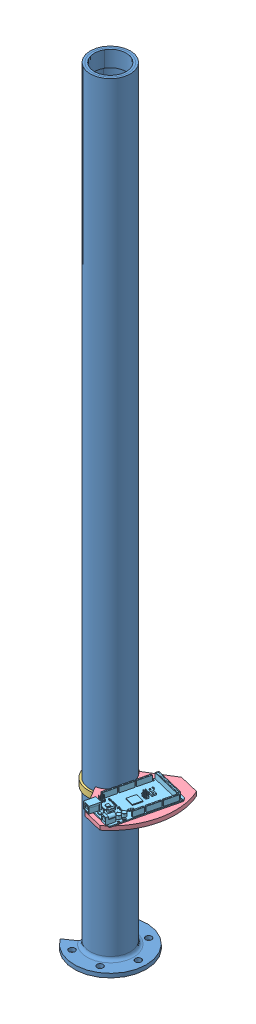
SolidWorks assembly Assem2, configuration Default. Lengths in mm.
Overall size (171.96 1216.15 144.23).
5 component instances, 5 part files, 10 mates.
Components (placement in the parent):
- LinearAct-1: LinearAct [Default] at (531.164 176.228 788.3631) size (103.96 1216.15 114.3)
- elec_right-1: elec_right [Default] at (531.164 411.1336 788.3631) x (-0.233481 0 0.972361) z (0.972361 0 0.233481) size (41.49 10.16 97.03)
- elec_left-1: elec_left [Default] at (531.164 400.9736 788.3631) x (0.233481 0 -0.972361) z (0.972361 0 0.233481) size (41.49 10.16 97.03)
- elec_platform-1: elec_platform [Default] at (631.4377 411.1336 812.4406) x (0.233481 0 -0.972361) z (0.972361 0 0.233481) size (127 6.35 88.85)
- ArduinoMega-1: ArduinoMega [Default] at (591.4633 419.1346 809.3726) x (-0.233481 0 0.972361) z (0 -1 0) size (107.95 53.42 12.95)
Mates (geometry in assembly coordinates):
- Concentric1: concentric aligned: cylinder of LinearAct-1 through (531.164 1392.38 788.3631) axis (0 -1 0) radius 31.75; cylinder of elec_left-1 through (531.164 411.1336 788.3631) axis (0 -1 0) radius 32.004
- Concentric2: concentric anti-aligned: cylinder of LinearAct-1 through (531.164 1392.38 788.3631) axis (0 -1 0) radius 31.75; cylinder of elec_right-1 through (531.164 400.9736 788.3631) axis (0 1 0) radius 32.004
- Coincident1: coincident anti-aligned: plane of elec_right-1 through (562.2834 400.9736 795.8355) normal (-0.233481 0 0.972361); plane of elec_left-1 through (562.2834 411.1336 795.8355) normal (0.233481 0 -0.972361)
- Coincident2: coincident aligned: plane of elec_right-1 through (531.164 411.1336 788.3631) normal (0 1 0); plane of elec_left-1 through (531.164 411.1336 788.3631) normal (0 1 0)
- Concentric10: concentric aligned: cylinder of LinearAct-1 through (531.164 1392.38 788.3631) axis (0 -1 0) radius 31.75; cylinder of elec_platform-1 through (531.164 417.4836 788.3631) axis (0 -1 0) radius 32.004
- Coincident6: coincident aligned: plane of elec_left-1 through (539.222 406.0536 820.9599) normal (-0.852659 0 0.522467); plane of elec_platform-1 through (538.357 417.4836 819.5483) normal (-0.852659 0 0.522467)
- Coincident7: coincident anti-aligned: plane of elec_left-1 through (531.164 411.1336 788.3631) normal (0 1 0); plane of elec_platform-1 through (531.164 411.1336 788.3631) normal (0 -1 0)
- Coincident8: coincident anti-aligned: plane of elec_platform-1 through (531.164 417.4836 788.3631) normal (0 1 0); plane of ArduinoMega-1 through (605.5724 417.4836 865.0044) normal (0 -1 0)
- Distance1: distance = 6.35 mm aligned: plane of ArduinoMega-1 through (553.6326 417.4836 852.5327) normal (-0.233481 0 0.972361); plane of elec_platform-1 through (564.1116 417.4836 861.5794) normal (-0.233481 0 0.972361)
- Distance2: distance = 5.08 mm anti-aligned: plane of ArduinoMega-1 through (577.3543 417.4836 753.7408) normal (-0.972361 0 -0.233481); cylinder of LinearAct-1 through (531.164 1392.38 788.3631) axis (0 -1 0) radius 31.75
